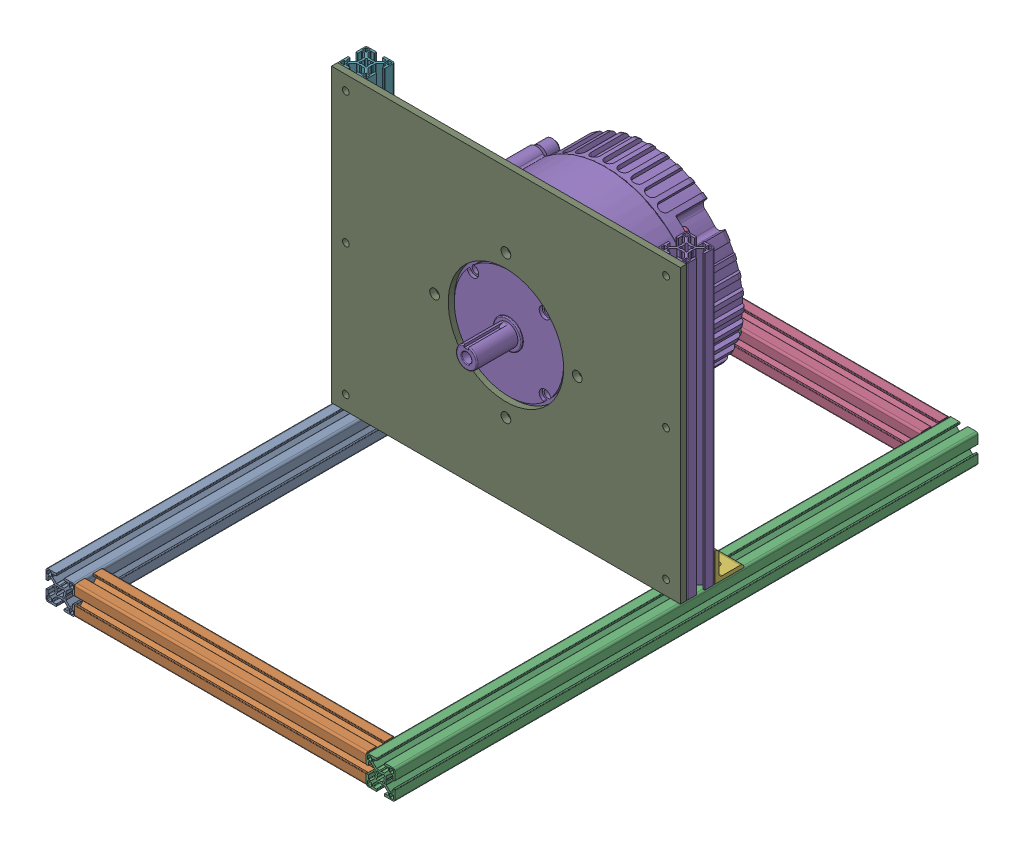
SolidWorks assembly TestStandCAD, configuration Default. Lengths in mm.
Overall size (364.8 334.8 609.6).
10 component instances, 5 part files, 27 mates.
Components (placement in the parent):
- 3030 X 24in-1: 3030 X 24in [30-3030] at (-75.7481 4.3977 261.1357) size (30 30 609.6)
- 3030 X 12in-1: 3030 X 12in [30-3030] at (244.0519 4.3977 246.1358) x (0 0 -1) z (1 0 0) size (30 30 304.8)
- 3030 X 24in-2: 3030 X 24in [30-3030] at (259.0518 4.3977 261.1357) size (30 30 609.6)
- 3030 X 12in-2: 3030 X 12in [30-3030] at (244.0519 4.3977 -333.4643) x (0 -1 0) z (1 0 0) size (30 30 304.8)
- 3030 X 12in-3: 3030 X 12in [30-3030] at (259.0518 19.3976 -58.6642) x (0 0 1) z (0 -1 0) size (30 30 304.8)
- 8020-30-4302-BLACK-1: 8020-30-4302-BLACK [Default] at (260.5517 19.3976 -73.6642) x (0 0 -1) z (1 0 0) size (30 30 27)
- 3030 X 12in-4: 3030 X 12in [30-3030] at (-75.7481 324.1976 -58.6642) x (-1 0 0) z (0 1 0) size (30 30 304.8)
- 8020-30-4302-BLACK-2: 8020-30-4302-BLACK [Default] at (-77.248 19.3976 -73.6642) x (0 0 -1) z (1 0 0) size (30 30 27)
- ME1917 Mounting Plate-1: ME1917 Mounting Plate [Default] at (-10.5475 113.8984 -43.6643) size (364.8 304.8 6.35)
- me1117-2: me1117 [Default] at (91.6517 171.7976 -43.6643) x (-1 0 0) z (0 0 -1) size (201 201 230.23)
Mates (geometry in assembly coordinates):
- Coincident50: coincident aligned: plane of 3030 X 24in-1 through (-62.5056 -0.1023 261.1357) normal (0 0 1); plane of 3030 X 12in-1 through (-60.7481 17.3976 261.1357) normal (0 0 1)
- Coincident51: coincident anti-aligned: plane of 3030 X 24in-1 through (-60.7481 8.8977 -348.4643) normal (1 0 0); plane of 3030 X 12in-1 through (-60.7481 -0.1023 232.8933) normal (-1 0 0)
- Coincident52: coincident aligned: plane of 3030 X 24in-1 through (-62.7481 19.3976 -348.4643) normal (0 1 0); plane of 3030 X 12in-1 through (-60.7481 19.3976 233.1358) normal (0 1 0)
- Coincident53: coincident aligned: plane of 3030 X 12in-1 through (-60.7481 17.3976 261.1357) normal (0 0 1); plane of 3030 X 24in-2 through (272.2943 -0.1023 261.1357) normal (0 0 1)
- Coincident54: coincident anti-aligned: plane of 3030 X 12in-1 through (244.0519 -0.1023 232.8933) normal (1 0 0); plane of 3030 X 24in-2 through (244.0519 17.3976 -348.4643) normal (-1 0 0)
- Coincident55: coincident aligned: plane of 3030 X 12in-1 through (-60.7481 -10.6023 259.1357) normal (0 -1 0); plane of 3030 X 24in-2 through (246.0518 -10.6023 -348.4643) normal (0 -1 0)
- Coincident56: coincident anti-aligned: plane of 3030 X 24in-2 through (244.0519 17.3976 -348.4643) normal (-1 0 0); plane of 3030 X 12in-2 through (244.0519 -8.8448 -328.9643) normal (1 0 0)
- Coincident57: coincident aligned: plane of 3030 X 24in-2 through (272.2943 -0.1023 -348.4643) normal (0 0 -1); plane of 3030 X 12in-2 through (-60.7481 8.8977 -348.4643) normal (0 0 -1)
- Coincident58: coincident aligned: plane of 3030 X 24in-2 through (254.5518 19.3976 -348.4643) normal (0 1 0); plane of 3030 X 12in-2 through (-60.7481 19.3976 -346.4643) normal (0 1 0)
- Coincident59: coincident anti-aligned: plane of 3030 X 24in-2 through (272.0517 19.3976 -348.4643) normal (0 1 0); plane of 3030 X 12in-3
- Coincident60: coincident aligned: plane of 3030 X 24in-2 through (274.0517 8.8977 -348.4643) normal (1 0 0); plane of 3030 X 12in-3
- Distance1: distance = 304.8 mm anti-aligned: plane of 3030 X 12in-3 through (272.0517 324.1976 -43.6643) normal (0 0 1); plane of 3030 X 24in-2 through (272.2943 -0.1023 -348.4643) normal (0 0 -1)
- Coincident62: coincident anti-aligned: plane of 3030 X 24in-2 through (272.0517 19.3976 -348.4643) normal (0 1 0); plane of 8020-30-4302-BLACK-1 through (247.0517 19.3976 -73.6642) normal (0 -1 0)
- Coincident63: coincident anti-aligned: plane of 3030 X 12in-3 through (263.5518 324.1976 -73.6642) normal (0 0 -1); plane of 8020-30-4302-BLACK-1 through (247.0517 19.3976 -73.6642) normal (0 0 1)
- Distance2: distance = 0 mm aligned: plane of 8020-30-4302-BLACK-1 through (274.0517 45.8976 -74.1642) normal (1 0 0); plane of 3030 X 12in-3 through (274.0517 324.1976 -71.6642) normal (1 0 0)
- Coincident65: coincident: plane of 3030 X 24in-1 through (-62.7481 19.3976 -348.4643) normal (0 1 0); plane of 3030 X 12in-4 through (-88.9906 19.3976 -63.1642) normal (0 -1 0)
- Coincident66: coincident: plane of 3030 X 24in-1 through (-90.748 17.3976 -348.4643) normal (-1 0 0); plane of 3030 X 12in-4 through (-90.748 19.3976 -71.6642) normal (-1 0 0)
- Distance3: distance = 304.8 mm anti-aligned: plane of 3030 X 12in-4 through (-88.748 19.3976 -43.6643) normal (0 0 1); plane of 3030 X 24in-1 through (-62.5056 -0.1023 -348.4643) normal (0 0 -1)
- Coincident68: coincident: plane of 3030 X 12in-4 through (-62.7481 19.3976 -73.6642) normal (0 0 -1); plane of 8020-30-4302-BLACK-2 through (-90.748 19.3976 -73.6642) normal (0 0 1)
- Coincident69: coincident: plane of 3030 X 24in-1 through (-62.7481 19.3976 -348.4643) normal (0 1 0); plane of 8020-30-4302-BLACK-2 through (-90.748 19.3976 -73.6642) normal (0 -1 0)
- Coincident70: coincident aligned: plane of 3030 X 12in-4 through (-90.748 19.3976 -71.6642) normal (-1 0 0); plane of 8020-30-4302-BLACK-2 through (-90.748 45.8976 -74.1642) normal (-1 0 0)
- Coincident71: coincident: plane of 3030 X 12in-3 through (254.5518 324.1976 -43.6643) normal (0 0 1); plane of ME1917 Mounting Plate-1 through (-10.5475 113.8984 -43.6643) normal (0 0 -1)
- Coincident72: coincident: plane of 3030 X 12in-3 through (274.0517 324.1976 -54.1642) normal (1 0 0); plane of ME1917 Mounting Plate-1 through (274.0517 113.8984 -37.3143) normal (1 0 0)
- Coincident73: coincident aligned: plane of 3030 X 12in-3 through (263.5518 324.1976 -45.4217) normal (0 1 0); plane of ME1917 Mounting Plate-1 through (-10.5475 324.1976 -37.3143) normal (0 1 0)
- Coincident74: coincident: plane of ME1917 Mounting Plate-1 through (-10.5475 113.8984 -43.6643) normal (0 0 -1); plane of me1117-2 through (91.6517 254.426 -43.6643) normal (0 0 1)
- Concentric1: concentric: circle of ME1917 Mounting Plate-1; circle of me1117-2
- Concentric2: concentric anti-aligned: circle of ME1917 Mounting Plate-1; circle of me1117-2
